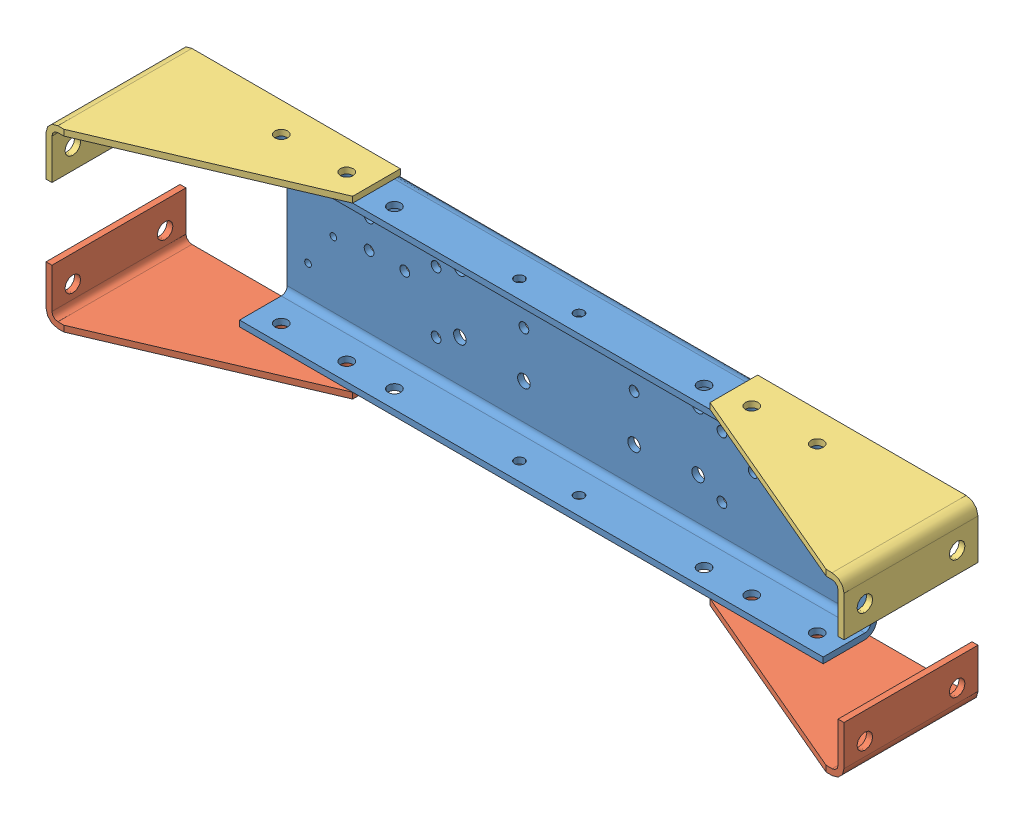
SolidWorks assembly SUB-1700-120, configuration Collapsed - No fasteners. Lengths in mm.
Overall size (850.9 187.32 149.22).
21 component instances, 5 part files, 58 mates.
Components (placement in the parent):
- 2504-CC2-2: 2504-CC2 [Default] x (-1 0 0) z (0 0 -1)
- 2723-CC2-1: 2723-CC2 [2723-CC2-001] at (-190.5 -93.6625 6.35) x (0 0 -1) z (-1 0 0)
- 2723-CC2-2: 2723-CC2 [2723-CC2-002] at (190.5 17.0815 6.35) x (0 0 -1) z (1 0 0)
- 2725-CC2-4: 2725-CC2 [2725-CC1-002] at (-419.1 87.3125 6.35) x (-1 0 0) z (0 0 -1)
- 2725-CC2-3: 2725-CC2 [2725-CC1-001] at (419.1 87.3125 6.35)
- 08130XXXFH8Y-8: 08130XXXFH8Y [08130125FH8Y] at (-285.75 -93.6625 38.1) x (0.633501 0 -0.773742) z (0 -1 0) (suppressed, hidden)
- 08130XXXFH8Y-7: 08130XXXFH8Y [08130125FH8Y] at (215.9 93.6625 38.1) x (-0.919879 0 -0.392203) z (0 1 0) (suppressed, hidden)
- 08130XXXFH8Y-6: 08130XXXFH8Y [08130125FH8Y] at (-285.75 93.6625 38.1) x (0.626948 0 -0.779061) z (0 1 0) (suppressed, hidden)
- 08130XXXFH8Y-5: 08130XXXFH8Y [08130125FH8Y] at (215.9 -93.6625 38.1) x (-0.995273 0 -0.097113) z (0 -1 0) (suppressed, hidden)
- 08130XXXFH8Y-4: 08130XXXFH8Y [08130125FH8Y] at (285.75 93.6625 38.1) x (-0.58028 0 0.814417) z (0 1 0) (suppressed, hidden)
- 08130XXXFH8Y-2: 08130XXXFH8Y [08130125FH8Y] at (-215.9 -93.6625 38.1) x (-0.002154 0 0.999998) z (0 -1 0) (suppressed, hidden)
- 08130XXXFH8Y-1: 08130XXXFH8Y [08130125FH8Y] at (-215.9 93.6625 38.1) x (-0.795507 0 0.605944) z (0 1 0) (suppressed, hidden)
- 08130XXXFH8Y-3: 08130XXXFH8Y [08130125FH8Y] at (285.75 -93.6625 38.1) x (0.864946 0 0.501864) z (0 -1 0) (suppressed, hidden)
- XXXXFLN8Y-6: XXXXFLN8Y [0813FLN8Y] at (-215.9 80.9625 38.1) x (-0.002154 0 0.999998) z (0 -1 0) (suppressed, hidden)
- XXXXFLN8Y-5: XXXXFLN8Y [0813FLN8Y] at (285.75 80.9625 38.1) x (-0.724046 0 -0.689752) z (0 -1 0) (suppressed, hidden)
- XXXXFLN8Y-2: XXXXFLN8Y [0813FLN8Y] at (-285.75 -80.9625 38.1) x (-0.002154 0 0.999998) z (0 1 0) (suppressed, hidden)
- XXXXFLN8Y-8: XXXXFLN8Y [0813FLN8Y] at (-215.9 -80.9625 38.1) x (-0.002154 0 0.999998) z (0 1 0) (suppressed, hidden)
- XXXXFLN8Y-3: XXXXFLN8Y [0813FLN8Y] at (215.9 80.9625 38.1) x (-0.724046 0 -0.689752) z (0 -1 0) (suppressed, hidden)
- XXXXFLN8Y-7: XXXXFLN8Y [0813FLN8Y] at (-285.75 80.9625 38.1) x (-0.002154 0 0.999998) z (0 -1 0) (suppressed, hidden)
- XXXXFLN8Y-4: XXXXFLN8Y [0813FLN8Y] at (285.75 -80.9625 38.1) x (0.864946 0 0.501864) z (0 1 0) (suppressed, hidden)
- XXXXFLN8Y-1: XXXXFLN8Y [0813FLN8Y] at (215.9 -80.9625 38.1) x (-0.724046 0 -0.689752) z (0 1 0) (suppressed, hidden)
Mates (geometry in assembly coordinates):
- Concentric15: concentric anti-aligned: cylinder of ?; cylinder of ?
- Concentric19: concentric anti-aligned: cylinder of ?; cylinder of ?
- Concentric20: concentric anti-aligned: cylinder of ?; cylinder of ?
- Concentric25: concentric anti-aligned: cylinder of ?; cylinder of ?
- Parallel3: parallel aligned: plane of ?; plane of ?
- Parallel5: parallel aligned: plane of ?; plane of ?
- Parallel6: parallel aligned: plane of ?; plane of ?
- Parallel7: parallel aligned: plane of ?; plane of ?
- Parallel9: parallel aligned: plane of ?; plane of ?
- Parallel11: parallel aligned: plane of ?; plane of ?
- Parallel13: parallel aligned: plane of ?; plane of ?
- Parallel14: parallel aligned: plane of ?; plane of ?
- Parallel18: parallel anti-aligned: plane of ?; plane of assembly
- Parallel19: parallel anti-aligned: plane of ?; plane of assembly
- Coincident34: coincident anti-aligned: plane of ?; plane of ?
- Coincident37: coincident anti-aligned: unknown of 2504-CC2-2
- Coincident38: coincident aligned: unknown of 2504-CC2-2
- Coincident39: coincident anti-aligned: unknown of 2504-CC2-2
- Coincident41: coincident anti-aligned: unknown of 2504-CC2-2
- Concentric28: concentric aligned: unknown of 2504-CC2-2
- Coincident42: coincident anti-aligned: unknown of 2504-CC2-2
- Coincident43: coincident anti-aligned: unknown of 2504-CC2-2
- Parallel21: parallel aligned: plane of ?; plane of assembly
- Parallel22: parallel anti-aligned: plane of ?; plane of assembly
- Coincident44: coincident anti-aligned: plane of ?; plane of ?
- Coincident45: coincident anti-aligned: unknown of 2504-CC2-2
- Coincident47: coincident anti-aligned: plane of ?; plane of ?
- Coincident48: coincident anti-aligned: unknown of 2504-CC2-2
- Coincident49: coincident anti-aligned: plane of ?; plane of ?
- Concentric34: concentric aligned: unknown of 2504-CC2-2
- Concentric35: concentric aligned: unknown of 2504-CC2-2
- Coincident50: coincident anti-aligned: plane of ?; plane of ?
- Concentric36: concentric anti-aligned: cylinder of ?; cylinder of ?
- Concentric37: concentric anti-aligned: cylinder of ?; cylinder of ?
- Coincident51: coincident anti-aligned: plane of ?; plane of ?
- Concentric39: concentric aligned: unknown of 2504-CC2-2
- Concentric40: concentric anti-aligned: cylinder of ?; cylinder of ?
- Concentric41: concentric anti-aligned: cylinder of ?; cylinder of ?
- Concentric42: concentric aligned: unknown of 2504-CC2-2
- Concentric45: concentric aligned: unknown of 2504-CC2-2
- Coincident52: coincident anti-aligned: unknown of 2504-CC2-2
- Coincident53: coincident anti-aligned: plane of ?; plane of ?
- Concentric46: concentric anti-aligned: unknown of 2504-CC2-2
- Concentric48: concentric aligned: cylinder of ?; cylinder of ?
- Concentric49: concentric aligned: cylinder of ?; cylinder of ?
- Concentric50: concentric anti-aligned: unknown of 2504-CC2-2
- Concentric51: concentric aligned: cylinder of ?; cylinder of ?
- Concentric52: concentric anti-aligned: unknown of 2504-CC2-2
- Concentric53: concentric anti-aligned: unknown of 2504-CC2-2
- Coincident54: coincident anti-aligned: unknown of 2504-CC2-2
- Coincident57: coincident anti-aligned: unknown of 2504-CC2-2
- Coincident58: coincident anti-aligned: unknown of 2504-CC2-2
- Coincident59: coincident anti-aligned: unknown of 2504-CC2-2
- Coincident60: coincident anti-aligned: unknown of 2504-CC2-2
- Concentric54: concentric aligned: circle of ?; cylinder of ?
- Coincident61: coincident anti-aligned: plane of ?; plane of ?
- Coincident63: coincident anti-aligned: unknown of 2504-CC2-2
- Coincident64: coincident anti-aligned: unknown of 2504-CC2-2
